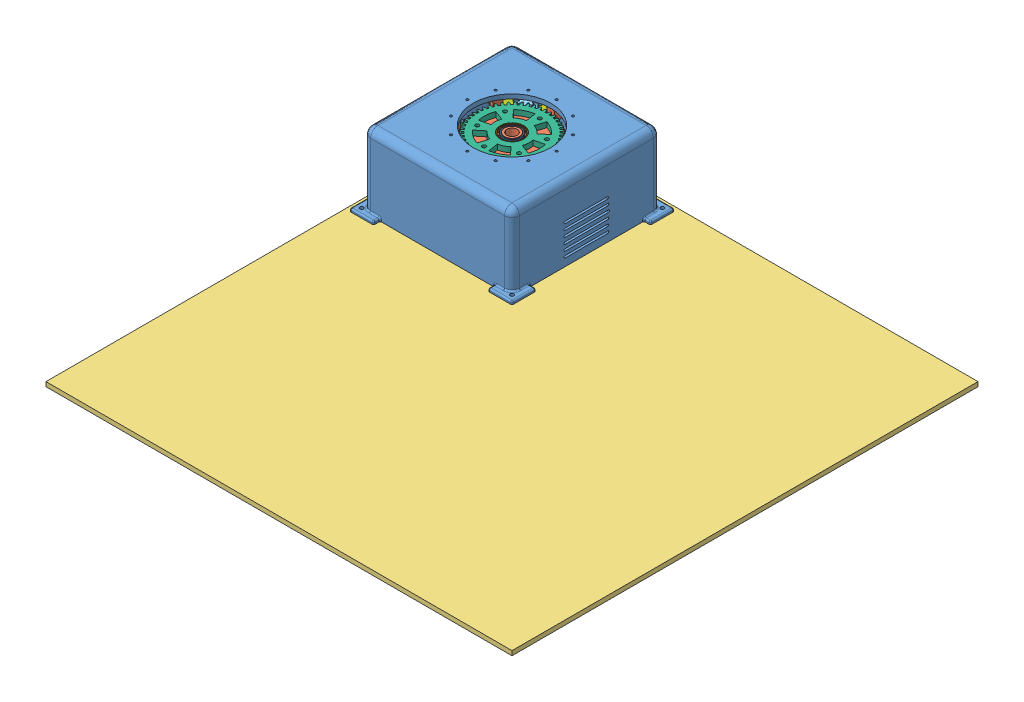
SolidWorks assembly assemblage bati en 2 piece, configuration Défaut. Lengths in mm.
Overall size (626 106 626).
12 component instances, 11 part files, 21 mates.
Components (placement in the parent):
- block bati 1v2-1: block bati 1v2 [Défaut] at (-148.1286 -3.1638 212.9499) size (218 100 218)
- block bati 2v2-1: block bati 2v2 [Défaut] at (-148.1286 90.8362 212.9499) size (116.43 14 131.28)
- plateau-1: plateau [Défaut] at (32.481 -9.1638 232.8281) x (1 0 0) z (0 1 0) size (626 626 8)
- transfo-1: transfo [Défaut] at (-12.6696 16.8362 275.5085) x (0 0 -1) z (1 0 0) size (160 31 100)
- roue sur pignon moteur-1: roue sur pignon moteur [Défaut] at (-26.1908 81.8362 184.7026) x (0.941029 0 0.338327) z (0 -1 0) size (27.86 27.86 7)
- grande roue pour epaule-1: grande roue pour epaule [Défaut] at (4.3304 88.8362 236.3597) x (-0.997596 0 -0.069295) z (-0.069295 0 0.997596) size (100 7 100)
- PM55L-048-1: PM55L-048 [Default] at (-16.5035 56.6362 147.0376) x (-0.860952 0 0.508687) z (0 1 0) size (82.5 64.72 41)
- carte-1: carte [Défaut] at (-78.5729 147.8051 284.228) x (0 1 0) z (1 0 0) size (70 95 40)
- bearing_61804_2-1: bearing_61804_2 [Default] at (4.3304 88.8362 236.3597) x (0 -1 0) z (0.375455 0 0.926841) size (7 32 32)
  - bearing_61804_2_01-1: bearing_61804_2_01 [Default] at origin size (7 32 32)
  - bearing_61804_2_02-1: bearing_61804_2_02 [Default] at origin size (7 23.85 23.85)
  - bearing_61804_2_03-1: bearing_61804_2_03 [Default] at origin size (3.5 29.12 29.31)
Mates (geometry in assembly coordinates):
- Coaxiale1: concentric anti-aligned: cylinder of block bati 1-1 through (4.3304 71.8362 176.3597) axis (0 1 0) radius 1.6; cylinder of block bati 2v2-1 through (4.3304 96.8362 176.3597) axis (0 -1 0) radius 1.6
- Coïncidente1: coincident anti-aligned: plane of block bati 1-1 through (-148.1286 90.8362 212.9499) normal (0 -1 0); plane of block bati 2v2-1 through (124.3304 90.8362 136.3597) normal (0 1 0)
- Coaxiale3: concentric anti-aligned: cylinder of block bati 1-1 through (105.3304 -9.1638 135.3597) axis (0 1 0) radius 2.5; cylinder of plateau-1 through (105.3304 -3.1638 135.3597) axis (0 -1 0) radius 2.5
- Coaxiale4: concentric anti-aligned: cylinder of block bati 1-1 through (105.3304 -9.1638 337.3597) axis (0 1 0) radius 2.5; cylinder of plateau-1 through (105.3304 -3.1638 337.3597) axis (0 -1 0) radius 2.5
- Coïncidente2: coincident anti-aligned: plane of block bati 1-1 through (-148.1286 -3.1638 212.9499) normal (0 -1 0); plane of plateau-1 through (32.481 -3.1638 232.8281) normal (0 1 0)
- Coïncidente3: coincident anti-aligned: plane of plateau-1 through (32.481 -3.1638 232.8281) normal (0 1 0); plane of transfo-1 through (87.3304 -3.1638 323.3597) normal (0 -1 0)
- Coïncidente4: coincident anti-aligned: plane of plateau-1 through (-14.6696 -1.1638 323.3597) normal (0 0 -1); plane of transfo-1 through (87.3304 27.8362 323.3597) normal (0 0 1)
- Coïncidente7: coincident anti-aligned: plane of plateau-1 through (87.3304 -1.1638 161.3597) normal (-1 0 0); plane of transfo-1 through (87.3304 16.8362 275.5085) normal (1 0 0)
- Coaxiale5: concentric anti-aligned: cylinder of block bati 2v2-1 through (4.3304 88.8362 236.3597) axis (0 -1 0) radius 10; cylinder of test grande roue-1 through (4.3304 78.8362 236.3597) axis (0 1 0) radius 15.75
- Coïncidente8: coincident anti-aligned: plane of plateau-1 through (32.481 -3.1638 232.8281) normal (0 1 0); plane of carte-1 through (-38.5729 -3.1638 331.3597) normal (0 -1 0)
- Coïncidente9: coincident anti-aligned: plane of block bati 2v2-1 through (4.3304 81.8362 236.3597) normal (0 1 0); plane of test grande roue-1 through (4.3304 81.8362 236.3597) normal (0 -1 0)
- Coaxiale9: concentric anti-aligned: cylinder of block bati 1-1 through (5.2339 79.8362 166.1356) axis (0 1 0) radius 4; cylinder of PM55L-048-1 through (5.2339 79.8362 166.1356) axis (0 -1 0) radius 2.25
- Coaxiale10: concentric aligned: cylinder of block bati 1-1 through (-57.6156 79.8362 203.2697) axis (0 1 0) radius 4; cylinder of PM55L-048-1 through (-57.6156 55.7829 203.2697) axis (0 1 0) radius 2.25
- Coïncidente10: coincident anti-aligned: plane of block bati 1-1 through (-148.1286 79.8362 212.9499) normal (0 -1 0); plane of PM55L-048-1 through (-49.867 79.8362 198.6915) normal (0 1 0)
- Coaxiale11: concentric anti-aligned: cylinder of test rou 1sur3 v2-1 through (-26.1908 91.8362 184.7026) axis (0 -1 0) radius 4.275; cylinder of PM55L-048-1 through (-26.1908 49.6362 184.7026) axis (0 1 0) radius 2
- Coïncidente11: coincident aligned: plane of test rou 1sur3 v2-1 through (-26.1908 88.8362 184.7026) normal (0 1 0); plane of test grande roue-1 through (4.3304 88.8362 236.3597) normal (0 1 0)
- Contr.Engrenages1: gear = 96 : 24 mm: circle of pignon pour pivot base epaule-1; circle of test grande roue-1
- Coïncidente13: coincident anti-aligned: plane of block bati 1-1 through (-90.6696 96.8362 331.3597) normal (0 0 -1); plane of carte-1 through (-38.5729 -3.1638 331.3597) normal (0 0 1)
- Coaxiale15: concentric anti-aligned: cylinder of block bati 1-1 through (56.2919 71.8362 206.3597) axis (0 1 0) radius 1.6; cylinder of block bati 2v2-1 through (56.2919 96.8362 206.3597) axis (0 -1 0) radius 1.6
- Coaxiale16: concentric anti-aligned: cylinder of block bati 2v2-1 through (4.3304 88.8362 236.3597) axis (0 -1 0) radius 10; cylinder of bearing_61804_2-1/bearing_61804_2_02-1 through (4.3304 85.3362 236.3597) axis (0 1 0) radius 10
- Coïncidente14: coincident aligned: plane of block bati 2v2-1 through (4.3304 88.8362 236.3597) normal (0 1 0); plane of bearing_61804_2-1/bearing_61804_2_02-1 through (14.7689 88.8362 232.1312) normal (0 1 0)
